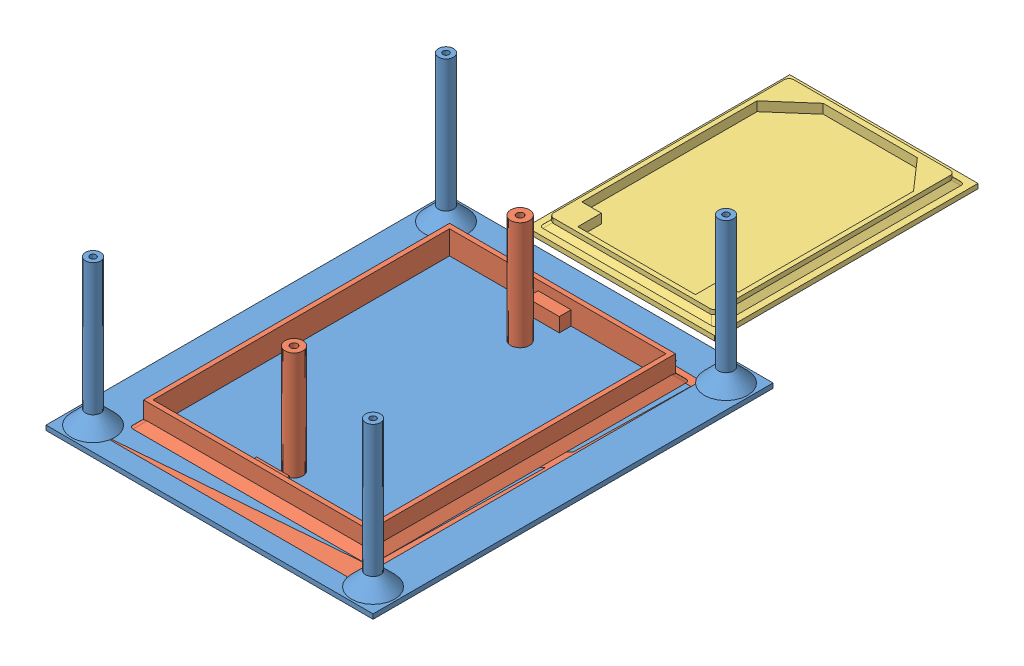
SolidWorks assembly дно корпуса, configuration По умолчанию. Lengths in mm.
Overall size (69.5 32 143.49).
3 component instances, 3 part files, 9 mates.
Components (placement in the parent):
- крепление платы-1: крепление платы [По умолчанию] at (-77.7422 5.0071 -9.6932) size (69.5 32 85)
- крепление-1: крепление [По умолчанию] at (-73.0667 6.0071 -15.0939) size (55 24 75)
- понижайка-1: понижайка [По умолчанию] at (-66.8795 5.0071 -59.6952) x (-1 0 0) z (0 0 -1) size (40 3 56)
Mates (geometry in assembly coordinates):
- Расстояние1: distance = 0 mm: plane of крепление-1 through (-73.0667 5.0071 -15.0939) normal (0 -1 0); plane of крепление платы-1 through (-77.7422 5.0071 -9.6932) normal (0 -1 0)
- Параллельность2: parallel: line of крепление платы-1 through (-106.3929 6.0071 42.5) axis (1 0 0); line of крепление-1 through (-99.936 6.0071 38.4159) axis (1 0 0)
- Параллельность3: parallel: line of крепление платы-1 through (-106.3929 6.0071 -42.5) axis (0 0 1); line of крепление-1 through (-99.936 6.0071 -36.5841) axis (0 0 1)
- Расстояние2: distance = 11.75 mm: line of крепление-1 through (-48.6429 6.0071 31.5) axis (0 0 -1); line of крепление платы-1 through (-36.8929 6.0071 42.5) axis (0 0 -1)
- Расстояние3: distance = 11 mm: line of крепление-1 through (-75.8208 6.0071 -31.5) axis (-1 0 0); line of крепление платы-1 through (-36.8929 6.0071 -42.5) axis (-1 0 0)
- Расстояние5: distance = 0 mm: plane of понижайка-1 through (-66.8795 5.0071 -59.6952) normal (0 -1 0); plane of крепление платы-1 through (-77.7422 5.0071 -9.6932) normal (0 -1 0)
- Параллельность7: parallel: line of крепление платы-1 through (-36.8929 6.0071 -42.5) axis (-1 0 0); line of понижайка-1 through (-92.7242 5.0071 -44.9931) axis (1 0 0)
- Расстояние6: distance = 17 mm: line of понижайка-1 through (-84.3929 6.0071 -48.5) axis (1 0 0); line of крепление-1 through (-48.6429 6.0071 -31.5) axis (-1 0 0)
- Расстояние7: distance = 18.375 mm: line of крепление платы-1 through (-36.8929 6.0071 42.5) axis (0 0 -1); line of понижайка-1 through (-55.2679 6.0071 -53.5) axis (0 0 -1)
